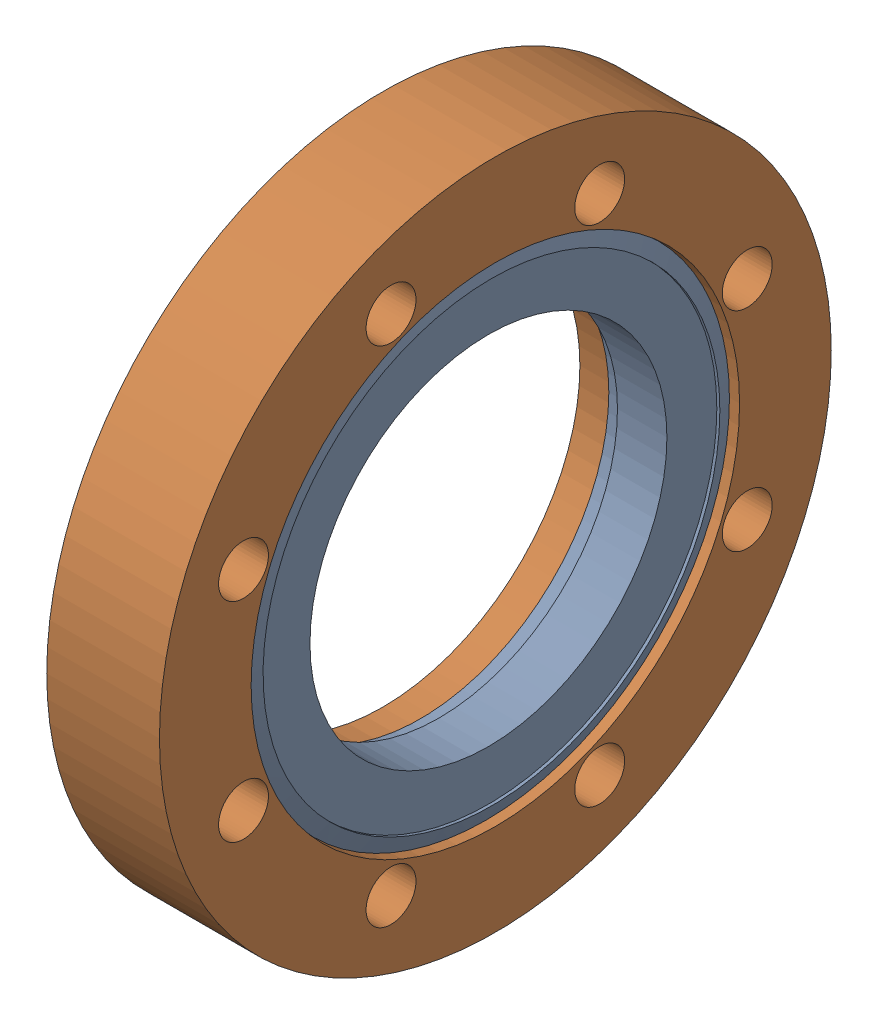
SolidWorks assembly 100021 (4.5 X 2.5 R), configuration Default. Lengths in mm.
Overall size (19.05 113.54 113.54).
2 component instances, 2 part files, 0 mates.
Components (placement in the parent):
- 100021 (4.5 X 2.5 INS)-1: 100021 (4.5 X 2.5 INS) [Default] at origin size (12.04 82.3 82.3)
- 100021 (4.5 X 2.5 REC)-1: 100021 (4.5 X 2.5 REC) [Default] at (-6.35 0 0) x (1 0 0) z (0 0 -1) size (19.05 113.54 113.54)
